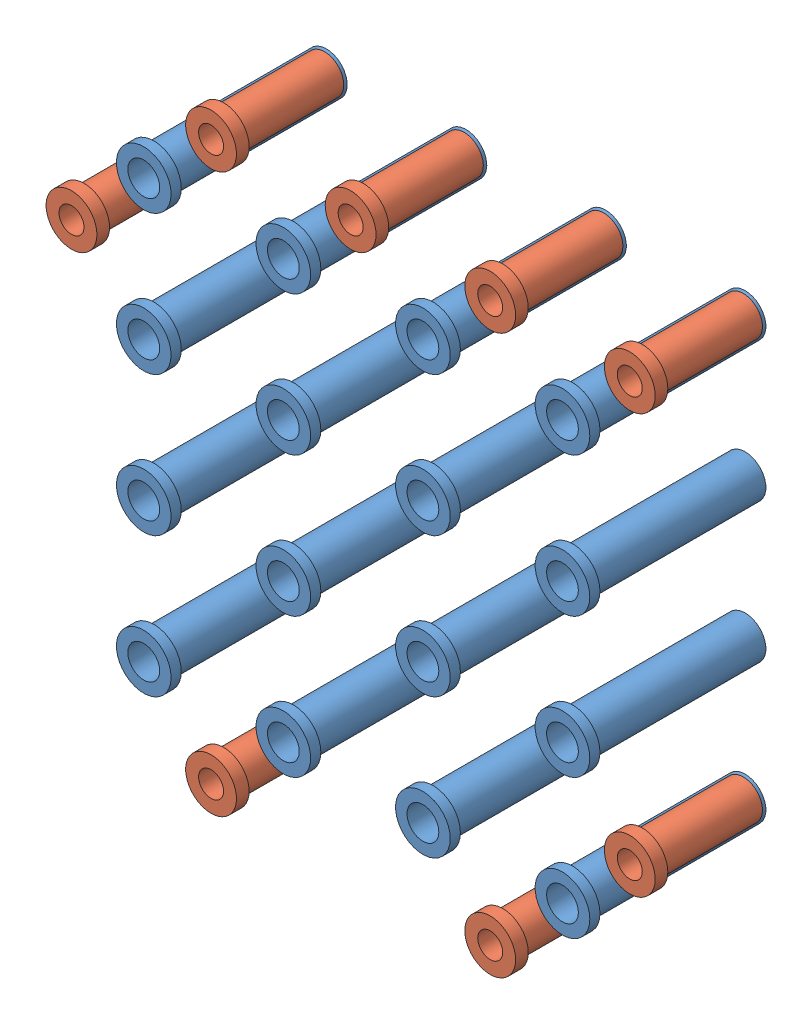
SolidWorks assembly SL10.4x4.pin-sockets, configuration Default. Lengths in mm.
Overall size (22.17 22.17 6.74).
25 component instances, 3 part files, 2 mates.
Components (placement in the parent):
- pin-socket.ED5008-1: pin-socket.ED5008 [Default] at (6.23 6.23 0) x (1 0 0) z (0 0 -1) size (1.99 1.99 6.65)
- pin-socket.ED5044-1: pin-socket.ED5044 [Default] at (24.01 24.01 0) x (1 0 0) z (0 0 -1) size (1.85 1.85 4.13)
- SL10.4x4.2D-1: SL10.4x4.2D [Default] at origin size (27.7 27.7 0) (hidden)
- pin-socket.ED5008-2: pin-socket.ED5008 [Default] at (6.23 11.31 0) x (1 0 0) z (0 0 -1) size (1.99 1.99 6.65)
- pin-socket.ED5008-3: pin-socket.ED5008 [Default] at (6.23 16.39 0) x (1 0 0) z (0 0 -1) size (1.99 1.99 6.65)
- pin-socket.ED5008-4: pin-socket.ED5008 [Default] at (6.23 21.47 0) x (1 0 0) z (0 0 -1) size (1.99 1.99 6.65)
- pin-socket.ED5008-5: pin-socket.ED5008 [Default] at (11.31 6.23 0) x (1 0 0) z (0 0 -1) size (1.99 1.99 6.65)
- pin-socket.ED5008-6: pin-socket.ED5008 [Default] at (11.31 11.31 0) x (1 0 0) z (0 0 -1) size (1.99 1.99 6.65)
- pin-socket.ED5008-7: pin-socket.ED5008 [Default] at (11.31 16.39 0) x (1 0 0) z (0 0 -1) size (1.99 1.99 6.65)
- pin-socket.ED5008-8: pin-socket.ED5008 [Default] at (11.31 21.47 0) x (1 0 0) z (0 0 -1) size (1.99 1.99 6.65)
- pin-socket.ED5008-9: pin-socket.ED5008 [Default] at (16.39 6.23 0) x (1 0 0) z (0 0 -1) size (1.99 1.99 6.65)
- pin-socket.ED5008-10: pin-socket.ED5008 [Default] at (16.39 11.31 0) x (1 0 0) z (0 0 -1) size (1.99 1.99 6.65)
- pin-socket.ED5008-11: pin-socket.ED5008 [Default] at (16.39 16.39 0) x (1 0 0) z (0 0 -1) size (1.99 1.99 6.65)
- pin-socket.ED5008-12: pin-socket.ED5008 [Default] at (16.39 21.47 0) x (1 0 0) z (0 0 -1) size (1.99 1.99 6.65)
- pin-socket.ED5008-13: pin-socket.ED5008 [Default] at (21.47 6.23 0) x (1 0 0) z (0 0 -1) size (1.99 1.99 6.65)
- pin-socket.ED5008-14: pin-socket.ED5008 [Default] at (21.47 11.31 0) x (1 0 0) z (0 0 -1) size (1.99 1.99 6.65)
- pin-socket.ED5008-15: pin-socket.ED5008 [Default] at (21.47 16.39 0) x (1 0 0) z (0 0 -1) size (1.99 1.99 6.65)
- pin-socket.ED5008-16: pin-socket.ED5008 [Default] at (21.47 21.47 0) x (1 0 0) z (0 0 -1) size (1.99 1.99 6.65)
- pin-socket.ED5044-4: pin-socket.ED5044 [Default] at (24.01 8.77 0) x (1 0 0) z (0 0 -1) size (1.85 1.85 4.13)
- pin-socket.ED5044-6: pin-socket.ED5044 [Default] at (18.93 24.01 0) x (1 0 0) z (0 0 -1) size (1.85 1.85 4.13)
- pin-socket.ED5044-10: pin-socket.ED5044 [Default] at (18.93 3.69 0) x (1 0 0) z (0 0 -1) size (1.85 1.85 4.13)
- pin-socket.ED5044-11: pin-socket.ED5044 [Default] at (13.85 24.01 0) x (1 0 0) z (0 0 -1) size (1.85 1.85 4.13)
- pin-socket.ED5044-16: pin-socket.ED5044 [Default] at (8.77 24.01 0) x (1 0 0) z (0 0 -1) size (1.85 1.85 4.13)
- pin-socket.ED5044-20: pin-socket.ED5044 [Default] at (8.77 3.69 0) x (1 0 0) z (0 0 -1) size (1.85 1.85 4.13)
- pin-socket.ED5044-22: pin-socket.ED5044 [Default] at (3.69 18.93 0) x (1 0 0) z (0 0 -1) size (1.85 1.85 4.13)
Mates (geometry in assembly coordinates):
- Coincident1: coincident anti-aligned: plane of pin-socket.ED5008-1 through (6.23 6.23 0) normal (0 0 -1); plane of assembly through (0 0 0) normal (0 0 1)
- Coincident3: coincident anti-aligned: plane of pin-socket.ED5044-1 through (24.01 24.01 0) normal (0 0 -1); plane of assembly through (0 0 0) normal (0 0 1)
